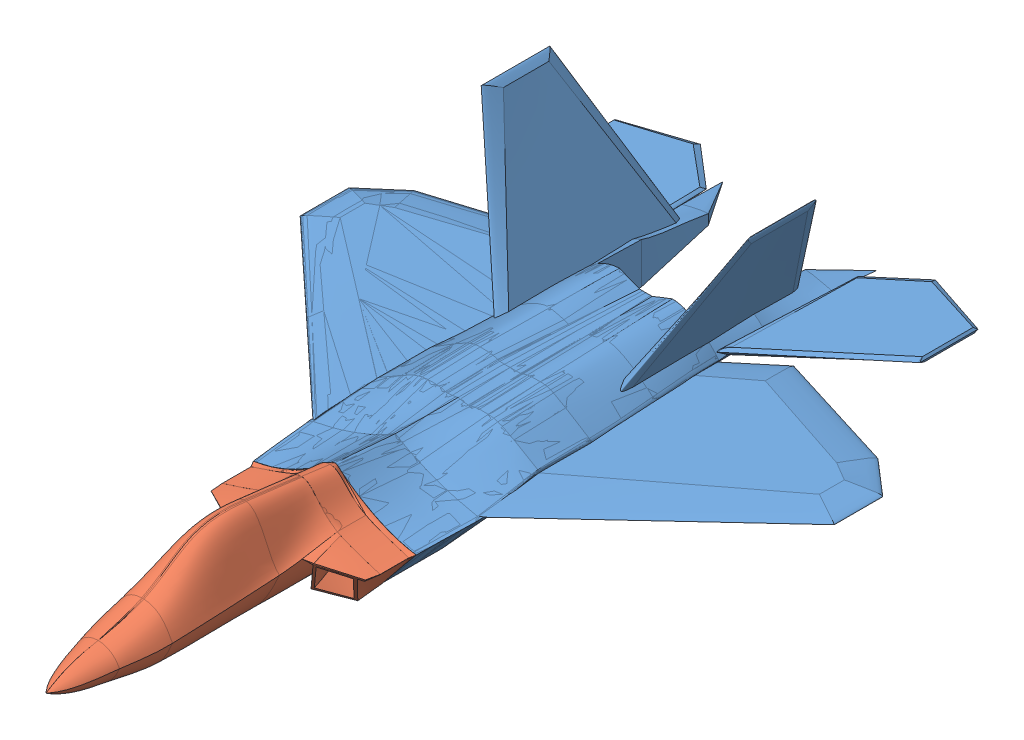
SolidWorks assembly Assem1, configuration Default. Lengths in mm.
Overall size (14299.45 5418.43 21136.23).
2 component instances, 2 part files, 3 mates.
Components (placement in the parent):
- 2nd part of jet-1: 2nd part of jet [Default] at (-76.6053 -1583.5631 14450.859) size (14299.45 5409.72 13405.48)
- Jet nose-1: Jet nose [Default] at (-76.6054 -1966.4328 14453.399) x (-1 0 0) z (0 0 -1) size (4356.45 2573.13 7735.99)
Mates (geometry in assembly coordinates):
- Tangent3: tangent: curve of Jet nose-1; curve of 2nd part of jet-1
- Tangent6: tangent: curve of 2nd part of jet-1; curve of Jet nose-1
- Lock1: lock: unknown of 2nd part of jet-1; unknown of Jet nose-1
